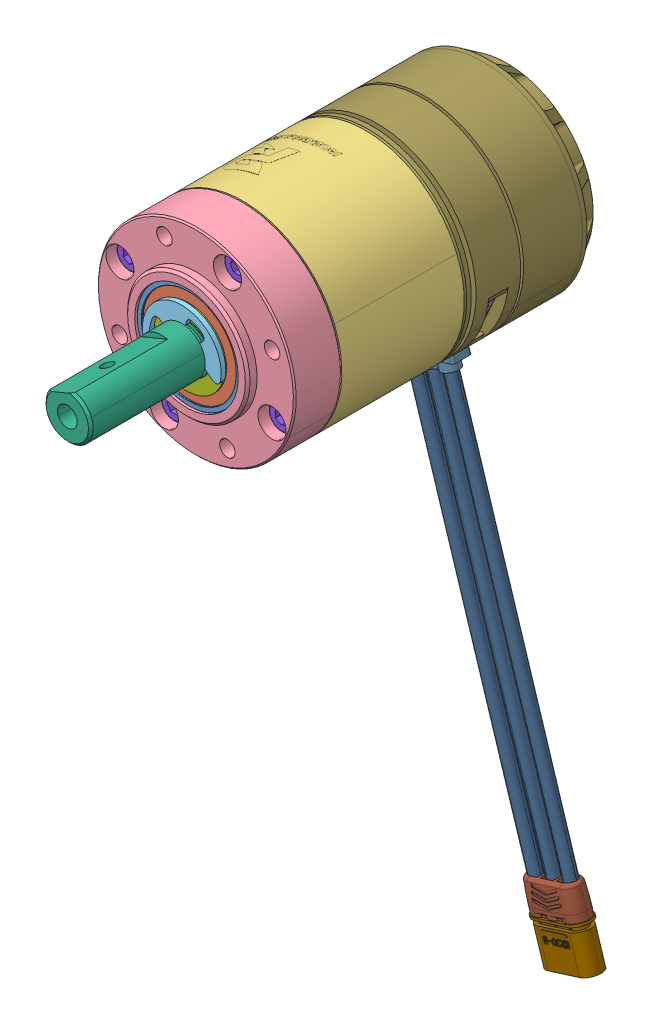
SolidWorks assembly M3508直流无刷减速电机, configuration 默认. Lengths in mm.
Overall size (81.79 158.79 98.4).
28 component instances, 14 part files, 0 mates.
Components (placement in the parent):
- M3508直流无刷减速电机.STEP-1: M3508直流无刷减速电机.STEP [Default] at origin size (81.79 158.79 98.4)
  - 2.STEP-1: 2.STEP [Default] at (-1.7887 18.2683 50.441) x (-0.381788 0.92425 0) z (0.92425 0.381788 0) size (59.4 63.3 59.4)
    - 26.STEP-1: 26.STEP [Default] at (0 27 0) x (-0.381788 0 0.92425) z (-0.92425 0 -0.381788) size (22 6 22)
      - 27.STEP-1: 27.STEP [默认] at origin size (22 6 22)
      - 28.STEP-1: 28.STEP [默认] at (0 2.5 0) size (20 0.2 20)
      - 28.STEP-2: 28.STEP [默认] at (0 -2.7 0) size (20 0.2 20)
    - 26.STEP-2: 26.STEP [Default] at (0 34.5 0) x (-0.381788 0 0.92425) z (-0.92425 0 -0.381788) size (22 6 22)
      - 27.STEP-1: 27.STEP [默认] at origin size (22 6 22)
      - 28.STEP-1: 28.STEP [默认] at (0 2.5 0) size (20 0.2 20)
      - 28.STEP-2: 28.STEP [默认] at (0 -2.7 0) size (20 0.2 20)
    - 23.STEP-1: 23.STEP [默认] at origin size (42.01 26 42)
    - 16.STEP-1: 16.STEP [默认] at (0 31 0) x (-0.707107 0 0.707107) z (0 1 0) size (42 42 14)
    - 25.STEP-1: 25.STEP [默认] at (0 38.5 0) x (0 0 1) z (-1 0 0) size (16.7 1 13.43)
    - 17.STEP-1: 17.STEP [默认] at (0 19.3 0) x (-1 0 0) z (0 0 -1) size (26 44 26)
    - 24.STEP-1: 24.STEP [默认] at (0 37.71 0) x (0 1 0) z (0.381788 0 -0.92425) size (0.42 16 16)
    - 18.STEP-1: 18.STEP [默认] at (12.3744 22 12.3744) x (-0.381788 0 0.92425) z (-0.92425 0 -0.381788) size (5.5 12 5.5)
    - 18.STEP-2: 18.STEP [默认] at (12.3744 22 -12.3744) x (0.92425 0 0.381788) z (-0.381788 0 0.92425) size (5.5 12 5.5)
    - 18.STEP-3: 18.STEP [默认] at (-12.3744 22 -12.3744) x (0.381788 0 -0.92425) z (0.92425 0 0.381788) size (5.5 12 5.5)
    - 18.STEP-4: 18.STEP [默认] at (-12.3744 22 12.3744) x (-0.92425 0 -0.381788) z (0.381788 0 -0.92425) size (5.5 12 5.5)
  - 5.STEP-1: 5.STEP [Default] at (56.824 -105.7062 43.091) x (0.954008 0.299781 0) z (-0.299781 0.954008 0) size (12.31 5.48 111.01)
    - 19.STEP-1: 19.STEP [默认] at origin size (12.31 5.48 13.41)
    - 15.STEP-1: 15.STEP [默认] at (-22.7519 0 22.9937) x (-1 0 0) z (0 0 -1) size (2.5 2.5 100)
    - 15.STEP-2: 15.STEP [默认] at (-18.7519 0 22.9937) x (0 1 0) z (0 0 -1) size (2.5 2.5 100)
    - 15.STEP-3: 15.STEP [默认] at (-14.7519 0 22.9937) x (-1 0 0) z (0 0 -1) size (2.5 2.5 100)
    - 20.STEP-1: 20.STEP [默认] at (-1.9783 -5.4851 11.3276) x (1 0 0) z (0 0 -1) size (11.93 4.93 6.5)
  - 1.STEP-1: 1.STEP [默认] at (-1.7887 18.2683 48.441) x (0.923508 -0.383579 0) z (0 0 1) size (42 42 43.4)
  - 4.STEP-1: 4.STEP [默认] at (-1.7887 18.2683 39.841) x (-0.923508 0.383579 0) z (0.383579 0.923508 0) size (13.16 4.25 21.29)
  - 3.STEP-1: 3.STEP [默认] at (4.5067 -1.7659 43.091) x (0.299781 -0.954008 0) z (0.954008 0.299781 0) size (5.77 4 14.5)
